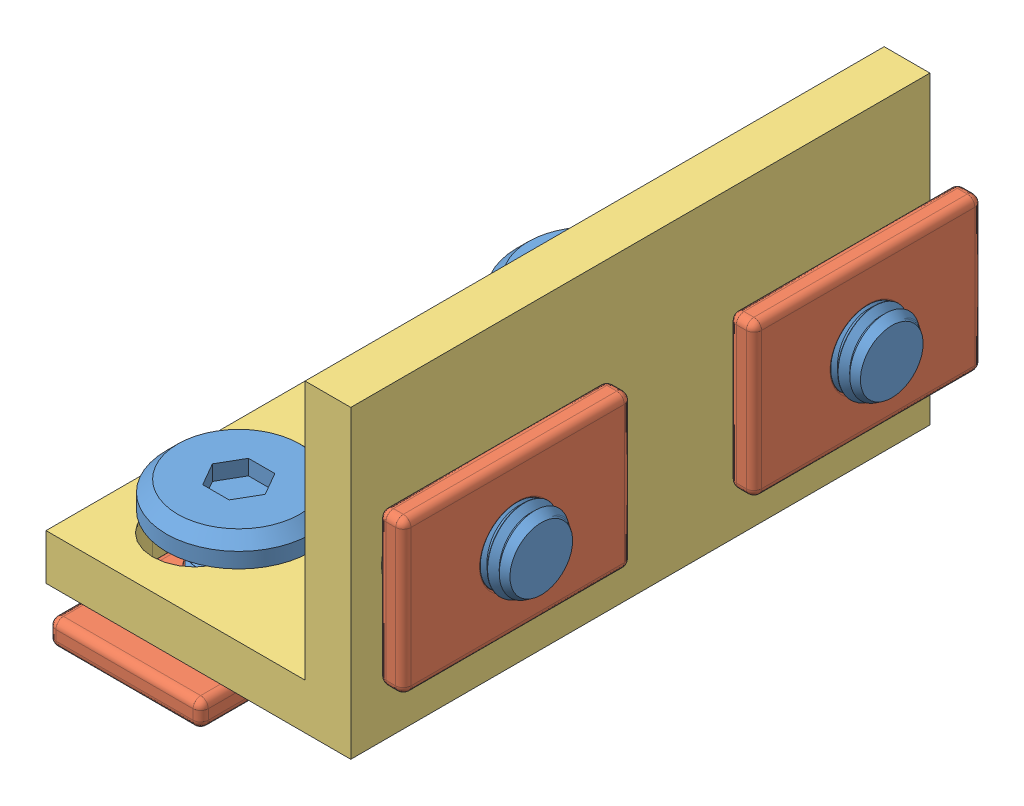
SolidWorks assembly Double Universal L-Bracket with Bolts and Tee Nuts, configuration Default. Lengths in mm.
Overall size (25.35 25.35 38).
13 component instances, 3 part files, 12 mates.
Components (placement in the parent):
- 5mm x 8mm Bolt with Tee Nut-1: 5mm x 8mm Bolt with Tee Nut [Default] at (-25.8297 5.7639 9.7141) size (10.1 10 15)
  - 5mm x 8mm Low Profile Socket Head Screw-1: 5mm x 8mm Low Profile Socket Head Screw [5mm x 8mm Low Profile] at (-34.8438 7.7195 10.4769) size (10.1 9.5 9.5)
  - Tee nut-1: Tee nut [Default] at (-28.2938 2.7205 17.9769) x (0 0 -1) z (1 0 0) size (15 10 3.3)
- Universal L Bracket - Double-1: Universal L Bracket - Double [Default] at (-55.9235 3.3334 -10.3091) x (0 0 -1) z (1 0 0) size (38 20 20)
- 5mm x 8mm Bolt with Tee Nut-2: 5mm x 8mm Bolt with Tee Nut [Default] at (-78.493 -26.7604 9.7141) x (0 -1 0) z (0 0 1) size (10.1 10 15)
  - 5mm x 8mm Low Profile Socket Head Screw-1: 5mm x 8mm Low Profile Socket Head Screw [5mm x 8mm Low Profile] at (-34.8438 7.7195 10.4769) size (10.1 9.5 9.5)
  - Tee nut-1: Tee nut [Default] at (-28.2938 2.7205 17.9769) x (0 0 -1) z (1 0 0) size (15 10 3.3)
- 5mm x 8mm Bolt with Tee Nut-3: 5mm x 8mm Bolt with Tee Nut [Default] at (-78.493 -26.7604 -13.2859) x (0 -1 0) z (0 0 1) size (10.1 10 15)
  - 5mm x 8mm Low Profile Socket Head Screw-1: 5mm x 8mm Low Profile Socket Head Screw [5mm x 8mm Low Profile] at (-34.8438 7.7195 10.4769) size (10.1 9.5 9.5)
  - Tee nut-1: Tee nut [Default] at (-28.2938 2.7205 17.9769) x (0 0 -1) z (1 0 0) size (15 10 3.3)
- 5mm x 8mm Bolt with Tee Nut-4: 5mm x 8mm Bolt with Tee Nut [Default] at (-25.8297 5.4639 -13.2859) size (10.1 10 15)
  - 5mm x 8mm Low Profile Socket Head Screw-1: 5mm x 8mm Low Profile Socket Head Screw [5mm x 8mm Low Profile] at (-34.8438 7.7195 10.4769) size (10.1 9.5 9.5)
  - Tee nut-1: Tee nut [Default] at (-28.2938 2.7205 17.9769) x (0 0 -1) z (1 0 0) size (15 10 3.3)
Mates (geometry in assembly coordinates):
- Coincident1: coincident anti-aligned: plane of 5mm x 8mm Bolt with Tee Nut-1/5mm x 8mm Low Profile Socket Head Screw-1 through (-58.9235 15.9834 20.1909) normal (1 0 0); plane of Universal L Bracket - Double-1 through (-58.9235 6.3334 27.6909) normal (-1 0 0)
- Coincident2: coincident aligned: plane of 5mm x 8mm Bolt with Tee Nut-1/Tee nut-1 through (-52.4735 8.4844 27.6909) normal (0 0 1); plane of Universal L Bracket - Double-1 through (-55.9235 3.3334 27.6909) normal (0 0 1)
- Tangent1: tangent anti-aligned: cylinder of 5mm x 8mm Bolt with Tee Nut-1/Tee nut-1 through (-55.7735 13.4834 20.1909) axis (1 0 0) radius 2.6; plane of Universal L Bracket - Double-1 through (-55.9235 16.0834 22.9409) normal (0 -1 0)
- Coincident3: coincident anti-aligned: plane of Universal L Bracket - Double-1 through (-58.9235 6.3334 27.6909) normal (-1 0 0); plane of 5mm x 8mm Bolt with Tee Nut-4/5mm x 8mm Low Profile Socket Head Screw-1 through (-58.9235 15.6834 -2.8091) normal (1 0 0)
- Coincident4: coincident aligned: plane of Universal L Bracket - Double-1 through (-55.9235 3.3334 -10.3091) normal (0 0 -1); plane of 5mm x 8mm Bolt with Tee Nut-4/Tee nut-1 through (-52.4735 8.1844 -10.3091) normal (0 0 -1)
- Tangent2: tangent anti-aligned: plane of Universal L Bracket - Double-1 through (-55.9235 10.5834 -5.5591) normal (0 1 0); cylinder of 5mm x 8mm Bolt with Tee Nut-4/Tee nut-1 through (-55.7735 13.1834 -2.8091) axis (1 0 0) radius 2.6
- Coincident5: coincident anti-aligned: plane of Universal L Bracket - Double-1 through (-75.9235 6.3334 27.6909) normal (0 1 0); plane of 5mm x 8mm Bolt with Tee Nut-2/5mm x 8mm Low Profile Socket Head Screw-1 through (-68.2735 6.3334 20.1909) normal (0 -1 0)
- Coincident6: coincident anti-aligned: plane of Universal L Bracket - Double-1 through (-75.9235 6.3334 27.6909) normal (0 1 0); plane of 5mm x 8mm Bolt with Tee Nut-3/5mm x 8mm Low Profile Socket Head Screw-1 through (-68.2735 6.3334 -2.8091) normal (0 -1 0)
- Coincident7: coincident aligned: plane of Universal L Bracket - Double-1 through (-55.9235 3.3334 27.6909) normal (0 0 1); plane of 5mm x 8mm Bolt with Tee Nut-2/Tee nut-1 through (-75.7725 -0.1166 27.6909) normal (0 0 1)
- Coincident8: coincident aligned: plane of Universal L Bracket - Double-1 through (-55.9235 3.3334 -10.3091) normal (0 0 -1); plane of 5mm x 8mm Bolt with Tee Nut-3/Tee nut-1 through (-75.7725 -0.1166 -10.3091) normal (0 0 -1)
- Tangent3: tangent anti-aligned: plane of Universal L Bracket - Double-1 through (-68.1735 3.3334 -5.5591) normal (-1 0 0); cylinder of 5mm x 8mm Bolt with Tee Nut-3/Tee nut-1 through (-70.7735 3.1834 -2.8091) axis (0 -1 0) radius 2.6
- Tangent4: tangent anti-aligned: plane of Universal L Bracket - Double-1 through (-68.1735 3.3334 22.9409) normal (-1 0 0); cylinder of 5mm x 8mm Bolt with Tee Nut-2/Tee nut-1 through (-70.7735 3.1834 20.1909) axis (0 -1 0) radius 2.6
